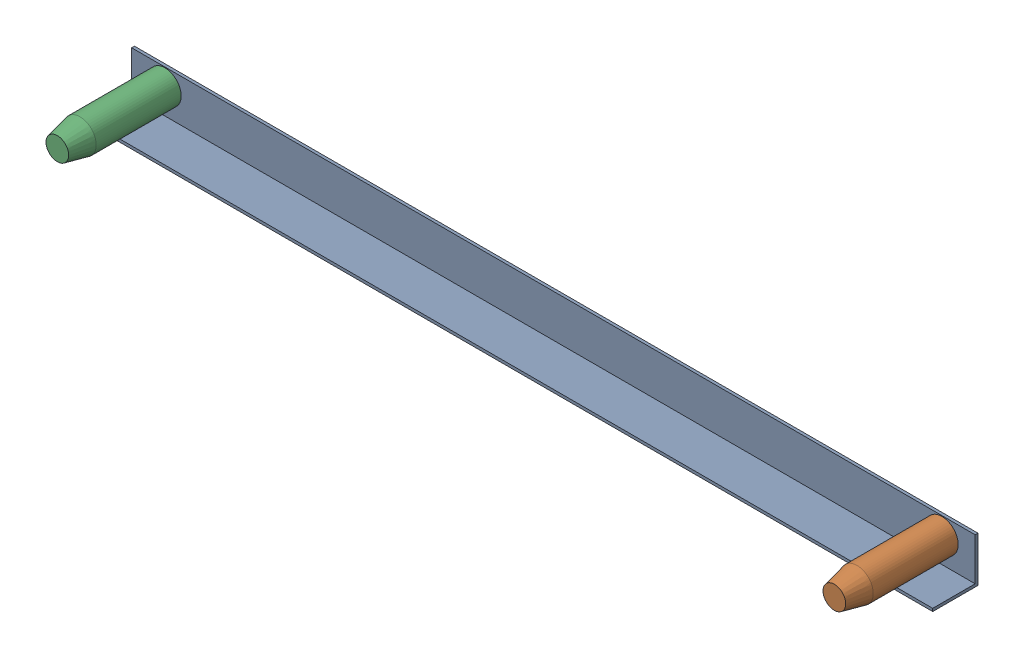
SolidWorks assembly GE-14036, configuration Default. Lengths in mm.
Overall size (946.15 50.8 123.83).
3 component instances, 2 part files, 0 mates.
Components (placement in the parent):
- GE-14036-01-1: GE-14036-01 [Default] at origin size (946.15 50.8 50.8)
- GE-14036-03-1: GE-14036-03 [Default] at (435.7687 3.175 95.25) x (-1 0 0) z (0 0 -1) size (36.51 36.51 120.65)
- GE-14036-03-2: GE-14036-03 [Default] at (-435.7687 3.175 95.25) x (-1 0 0) z (0 0 -1) size (36.51 36.51 120.65)
